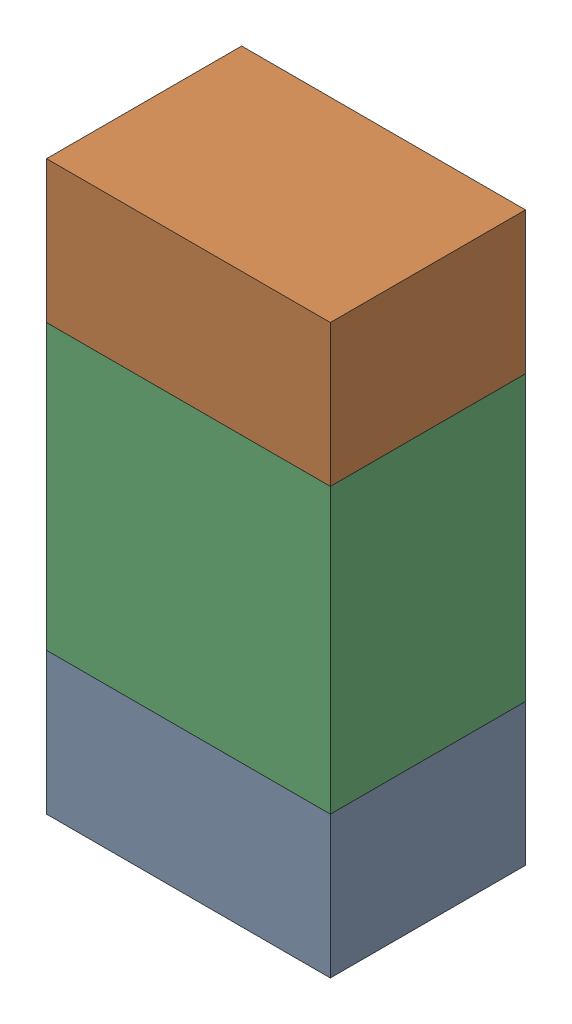
SolidWorks assembly R4, configuration ﾃﾞﾌｫﾙﾄ. Lengths in mm.
Overall size (0.8 1.6 0.55).
6 component instances, 2 part files, 0 mates.
Components (placement in the parent):
- 689261784-1: 689261784 [ﾃﾞﾌｫﾙﾄ] at (16.9999 24.1501 0) size (0.8 0.4 0.55)
  - Extruded_34-1: Extruded_34 [ﾃﾞﾌｫﾙﾄ] at origin size (0.8 0.4 0.55)
- 689261784-2: 689261784 [ﾃﾞﾌｫﾙﾄ] at (16.9999 25.3501 0) size (0.8 0.4 0.55)
  - Extruded_34-1: Extruded_34 [ﾃﾞﾌｫﾙﾄ] at origin size (0.8 0.4 0.55)
- 689261648-1: 689261648 [ﾃﾞﾌｫﾙﾄ] at (16.9999 24.75 0) size (0.8 0.8 0.55)
  - Extruded_33-1: Extruded_33 [ﾃﾞﾌｫﾙﾄ] at origin size (0.8 0.8 0.55)
